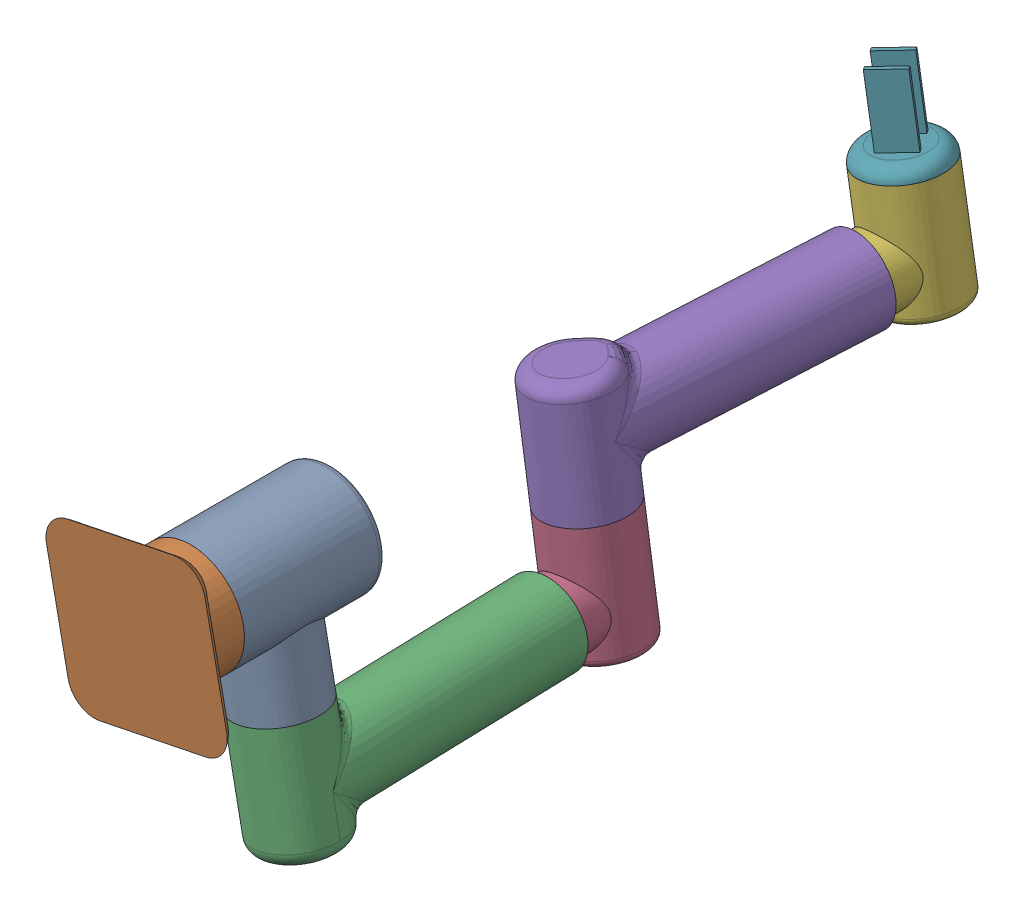
SolidWorks assembly Rotating_Arm, configuration Default. Lengths in mm.
Overall size (14.16 26.54 60.42).
7 component instances, 5 part files, 11 mates.
Components (placement in the parent):
- Rotator1-1: Rotator1 [Default] at (-3.3734 -1.0803 -1.7913) x (0.194886 -0.980826 0) z (0 0 1) size (12 8 10.5)
- Base-1: Base [Default] at (-3.3734 -1.0803 9.2087) x (-0.979807 -0.199944 0) z (0.199944 -0.979807 0) size (12 4 12)
- Long Link-1: Long Link [Default] at (-0.2552 -16.7735 1.1661) x (-0.03678 -0.007308 -0.999297) z (-0.194886 0.980826 0) size (22.61 6 8.5)
- Rotator2-1: Rotator2 [Default] at (-1.4045 -16.1092 -22.4195) x (0.03678 0.007308 0.999297) z (-0.151034 0.988527 -0.00167) size (7 6 8.5)
- Long Link-2: Long Link [Default] at (-3.821 -0.2928 -22.4462) x (0.062831 0.007913 -0.997993) z (0.151034 -0.988527 0.00167) size (22.61 6 8.5)
- Rotator2-2: Rotator2 [Default] at (-1.4006 -5.9601 -45.9926) x (-0.062831 -0.007913 0.997993) z (-0.167559 0.985858 -0.002732) size (7 6 8.5)
- Gripper-2: Gripper [Default] at (-2.741 1.9268 -46.0145) x (-0.566954 -0.098627 -0.817824) z (0.806528 0.135485 -0.575462) size (6 6 6)
Mates (geometry in assembly coordinates):
- Coincident1: coincident anti-aligned: circle of Part1-1; circle of Part2-1
- Concentric1: concentric aligned: cylinder of Part2-1 through (-3.3734 -1.0803 -3.7913) axis (0 0 1) radius 4; cylinder of Part1-1 through (-3.3734 -1.0803 6.2087) axis (0 0 1) radius 4
- Concentric2: concentric anti-aligned: cylinder of Part2-1 through (-4.1531 2.8439 1.1661) axis (0.194886 -0.980826 0) radius 3; cylinder of Part3-1 through (-0.2552 -16.7735 1.1661) axis (-0.194886 0.980826 0) radius 3
- Coincident2: coincident anti-aligned: plane of Part2-1 through (-1.8143 -8.9269 1.1661) normal (0.194886 -0.980826 0); plane of Part3-1 through (-1.8143 -8.9269 1.1661) normal (-0.194886 0.980826 0)
- Concentric3: concentric anti-aligned: cylinder of Part3-1 through (-0.8076 -13.4158 4.165) axis (-0.03678 -0.007308 -0.999297) radius 3; cylinder of Part5-1 through (-1.8967 -13.6322 -25.4226) axis (0.03678 0.007308 0.999297) radius 2.5
- Coincident3: coincident anti-aligned: circle of Part3-1; plane of Part5-1 through (-1.6392 -13.5811 -18.4265) normal (0.03678 0.007308 0.999297)
- Concentric4: concentric anti-aligned: cylinder of Part5-1 through (-1.4045 -16.1092 -22.4195) axis (-0.151034 0.988527 -0.00167) radius 3; cylinder of Part3-2 through (-3.821 -0.2928 -22.4462) axis (0.151034 -0.988527 0.00167) radius 3
- Coincident4: coincident anti-aligned: plane of Part5-1 through (-2.6127 -8.201 -22.4328) normal (-0.151034 0.988527 -0.00167); plane of Part3-2 through (-2.6127 -8.201 -22.4328) normal (0.151034 -0.988527 0.00167)
- Concentric5: concentric anti-aligned: cylinder of Part3-2 through (-3.4959 -3.6785 -19.4455) axis (0.062831 0.007913 -0.997993) radius 3; cylinder of Part5-2 through (-1.6356 -3.4442 -48.9945) axis (-0.062831 -0.007913 0.997993) radius 2.5
- Coincident7: coincident anti-aligned: plane of Part3-2 through (-2.0755 -3.4996 -42.0076) normal (0.062831 0.007913 -0.997993); plane of Part5-2 through (-2.0755 -3.4996 -42.0076) normal (-0.062831 -0.007913 0.997993)
- Coincident8: coincident aligned: circle of Part5-2; circle of Part6-2
